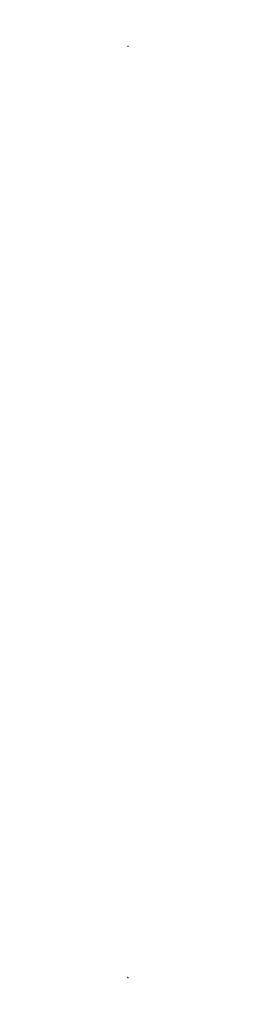
SolidWorks assembly PCB, configuration 默认. Lengths in mm.
Overall size (86.32 130845.02 99.24).
17 component instances, 7 part files, 34 mates.
Components (placement in the parent):
- MTi-600-series_dev_board_RTK-1: MTi-600-series_dev_board_RTK [默认] at origin size (85.78 22.45 98.7)
- support_v0731-1: support_v0731 [默认] at (-81.6803 0.2238 -42.0386) x (1 0 0) z (0 1 0) size (80 90 3)
- 3D_EverySyncBoard-1: 3D_EverySyncBoard [默认] at (-110.8303 11.2238 -45.0001) x (1 0 0) z (0 1 0) size (69.97 49.97 11.61)
- 3D_sync_ext_board-1: 3D_sync_ext_board [默认] at (-110.8413 130801.7057 -20.0185) x (0.000242 0 -1) z (0 -1 0) size (49.99 69.97 12.3)
- 3D_sync_ext_board-2: 3D_sync_ext_board [默认] at (-110.8301 -4.7762 -19.9999) x (0 0 -1) z (0 -1 0) size (49.99 69.97 12.3)
- 柱3×8-1: 柱3×8 [默认] at (-107.3302 3.2238 -23.5) x (0.724489 0 -0.689286) z (0.689286 0 0.724489) size (5 8 5)
- 柱3×8-2: 柱3×8 [默认] at (-107.3302 3.2238 -66.5) size (5 8 5)
- 柱3×8-3: 柱3×8 [默认] at (-44.3302 3.2238 -23.5) size (5 8 5)
- 柱3×8-4: 柱3×8 [默认] at (-44.3302 3.2238 -66.5) size (5 8 5)
- 柱3×5-1: 柱3×5 [默认] at (-107.3302 -4.7762 -66.4975) size (5 5 5)
- 柱3×5-2: 柱3×5 [默认] at (-107.3302 -4.7762 -23.5) x (0.99913 0 0.041703) z (-0.041703 0 0.99913) size (5 5 5)
- 柱3×5-3: 柱3×5 [默认] at (-44.3302 -4.7762 -66.5) x (0.971109 0 0.238638) z (-0.238638 0 0.971109) size (5 5 5)
- 柱3×5-4: 柱3×5 [默认] at (-44.3302 -4.7762 -23.5) x (0.996166 0 -0.08748) z (0.08748 0 0.996166) size (5 5 5)
- 柱3×35-1: 柱3×35 [默认] at (-38.8302 -34.7762 -3) x (-0.944478 0 -0.328574) z (0.328574 0 -0.944478) size (5 35 5)
- 柱3×35-2: 柱3×35 [默认] at (-112.8302 -34.7762 -3) x (0.707262 0 0.706951) z (-0.706951 0 0.707262) size (5 35 5)
- 柱3×35-3: 柱3×35 [默认] at (-38.8302 -34.7762 -87) size (5 35 5)
- 柱3×35-4: 柱3×35 [默认] at (-112.8302 -34.7762 -87) x (0.478155 0 -0.878275) z (0.878275 0 0.478155) size (5 35 5)
Mates (geometry in assembly coordinates):
- 同心3: concentric anti-aligned: cylinder of support_v0731-1 through (-44.3302 3.2248 -66.5) axis (0 -1 0) radius 1.65; cylinder of 3D_sync_ext_board-1 through (-44.3302 130801.7057 -66.5) axis (0 1 0) radius 1.6
- 同心4: concentric anti-aligned: cylinder of support_v0731-1 through (-44.3302 3.2248 -66.5) axis (0 -1 0) radius 1.65; cylinder of 3D_sync_ext_board-2 through (-44.3302 -4.7762 -66.5) axis (0 1 0) radius 1.6
- 同心5: concentric anti-aligned: cylinder of support_v0731-1 through (-107.3302 3.2248 -23.5) axis (0 -1 0) radius 1.65; cylinder of 3D_sync_ext_board-2 through (-107.3302 -4.7762 -23.5) axis (0 1 0) radius 1.6
- 同心9: concentric aligned: cylinder of support_v0731-1 through (-107.3302 3.2248 -23.5) axis (0 -1 0) radius 1.65; cylinder of 3D_EverySyncBoard-1 through (-107.3302 11.2238 -23.5) axis (0 -1 0) radius 1.6
- 同心10: concentric aligned: cylinder of support_v0731-1 through (-44.3302 3.2248 -66.5) axis (0 -1 0) radius 1.65; cylinder of 3D_EverySyncBoard-1 through (-44.3302 11.2238 -66.5) axis (0 -1 0) radius 1.6
- 同心11: concentric aligned: cylinder of support_v0731-1 through (-107.3302 3.2248 -23.5) axis (0 -1 0) radius 1.65; cylinder of 柱3×8-1 through (-107.3302 11.2238 -23.5) axis (0 -1 0) radius 1.5
- 重合1: coincident anti-aligned: plane of support_v0731-1 through (-81.6803 3.2238 -42.0386) normal (0 1 0); plane of 柱3×8-1 through (-107.3302 3.2238 -23.5) normal (0 -1 0)
- 重合2: coincident anti-aligned: plane of 3D_EverySyncBoard-1 through (-75.8303 11.2238 -45.0001) normal (0 -1 0); plane of 柱3×8-1 through (-107.3302 11.2238 -23.5) normal (0 1 0)
- 同心12: concentric aligned: cylinder of support_v0731-1 through (-107.3302 3.2248 -66.5) axis (0 -1 0) radius 1.65; cylinder of 柱3×8-2 through (-107.3302 11.2238 -66.5) axis (0 -1 0) radius 1.5
- 重合3: coincident anti-aligned: plane of support_v0731-1 through (-81.6803 3.2238 -42.0386) normal (0 1 0); plane of 柱3×8-2 through (-107.3302 3.2238 -66.5) normal (0 -1 0)
- 同心13: concentric aligned: cylinder of support_v0731-1 through (-44.3302 3.2248 -66.5) axis (0 -1 0) radius 1.65; cylinder of 柱3×8-4 through (-44.3302 11.2238 -66.5) axis (0 -1 0) radius 1.5
- 重合4: coincident anti-aligned: plane of support_v0731-1 through (-81.6803 3.2238 -42.0386) normal (0 1 0); plane of 柱3×8-4 through (-44.3302 3.2238 -66.5) normal (0 -1 0)
- 同心14: concentric aligned: cylinder of support_v0731-1 through (-44.3302 3.2248 -23.5) axis (0 -1 0) radius 1.65; cylinder of 柱3×8-3 through (-44.3302 11.2238 -23.5) axis (0 -1 0) radius 1.5
- 重合5: coincident anti-aligned: plane of support_v0731-1 through (-81.6803 3.2238 -42.0386) normal (0 1 0); plane of 柱3×8-3 through (-44.3302 3.2238 -23.5) normal (0 -1 0)
- 同心15: concentric anti-aligned: cylinder of 3D_sync_ext_board-2 through (-107.3302 -4.7762 -66.4975) axis (0 1 0) radius 1.6; cylinder of 柱3×5-1 through (-107.3302 0.2238 -66.4975) axis (0 -1 0) radius 1.5
- 重合6: coincident anti-aligned: plane of support_v0731-1 through (-81.6803 0.2238 -42.0386) normal (0 -1 0); plane of 柱3×5-1 through (-107.3302 0.2238 -66.4975) normal (0 1 0)
- 同心16: concentric aligned: cylinder of support_v0731-1 through (-107.3302 3.2248 -23.5) axis (0 -1 0) radius 1.65; cylinder of 柱3×5-2 through (-107.3302 0.2238 -23.5) axis (0 -1 0) radius 1.5
- 重合7: coincident anti-aligned: plane of support_v0731-1 through (-81.6803 0.2238 -42.0386) normal (0 -1 0); plane of 柱3×5-2 through (-107.3302 0.2238 -23.5) normal (0 1 0)
- 同心17: concentric aligned: cylinder of support_v0731-1 through (-44.3302 3.2248 -23.5) axis (0 -1 0) radius 1.65; cylinder of 柱3×5-4 through (-44.3302 0.2238 -23.5) axis (0 -1 0) radius 1.5
- 重合8: coincident anti-aligned: plane of support_v0731-1 through (-81.6803 0.2238 -42.0386) normal (0 -1 0); plane of 柱3×5-4 through (-44.3302 0.2238 -23.5) normal (0 1 0)
- 同心18: concentric aligned: cylinder of support_v0731-1 through (-44.3302 3.2248 -66.5) axis (0 -1 0) radius 1.65; cylinder of 柱3×5-3 through (-44.3302 0.2238 -66.5) axis (0 -1 0) radius 1.5
- 重合9: coincident anti-aligned: plane of support_v0731-1 through (-81.6803 0.2238 -42.0386) normal (0 -1 0); plane of 柱3×5-3 through (-44.3302 0.2238 -66.5) normal (0 1 0)
- 重合10: coincident anti-aligned: plane of 3D_sync_ext_board-2 through (-75.8301 -4.7762 -44.9999) normal (0 1 0); plane of 柱3×5-3 through (-44.3302 -4.7762 -66.5) normal (0 -1 0)
- 重合16: coincident anti-aligned: plane of MTi-600-series_dev_board_RTK-1 through (-35.8302 -34.7762 -0.9) normal (0 1 0); plane of 柱3×35-2 through (-112.8302 -34.7762 -3) normal (0 -1 0)
- 同心23: concentric aligned: cylinder of MTi-600-series_dev_board_RTK-1 through (-112.8302 -36.4182 -3) axis (0 -1 0) radius 1.55; cylinder of 柱3×35-2 through (-112.8302 0.2238 -3) axis (0 -1 0) radius 1.5
- 重合20: coincident anti-aligned: plane of MTi-600-series_dev_board_RTK-1 through (-35.8302 -34.7762 -0.9) normal (0 1 0); plane of 柱3×35-1 through (-38.8302 -34.7762 -3) normal (0 -1 0)
- 同心26: concentric aligned: cylinder of MTi-600-series_dev_board_RTK-1 through (-38.8302 -36.4182 -3) axis (0 -1 0) radius 1.55; cylinder of 柱3×35-1 through (-38.8302 0.2238 -3) axis (0 -1 0) radius 2.5
- 重合22: coincident anti-aligned: plane of MTi-600-series_dev_board_RTK-1 through (-35.8302 -34.7762 -0.9) normal (0 1 0); plane of 柱3×35-4 through (-112.8302 -34.7762 -87) normal (0 -1 0)
- 同心27: concentric aligned: cylinder of MTi-600-series_dev_board_RTK-1 through (-112.8302 -36.4182 -87) axis (0 -1 0) radius 1.55; cylinder of 柱3×35-4 through (-112.8302 0.2238 -87) axis (0 -1 0) radius 1.5
- 同心28: concentric aligned: cylinder of MTi-600-series_dev_board_RTK-1 through (-38.8302 -36.4182 -87) axis (0 -1 0) radius 1.55; cylinder of 柱3×35-3 through (-38.8302 0.2238 -87) axis (0 -1 0) radius 1.5
- 重合23: coincident anti-aligned: plane of MTi-600-series_dev_board_RTK-1 through (-35.8302 -34.7762 -0.9) normal (0 1 0); plane of 柱3×35-3 through (-38.8302 -34.7762 -87) normal (0 -1 0)
- 同心29: concentric aligned: cylinder of support_v0731-1 through (-38.8302 3.2238 -87) axis (0 -1 0) radius 1.65; cylinder of 柱3×35-3 through (-38.8302 0.2238 -87) axis (0 -1 0) radius 1.5
- 同心30: concentric aligned: cylinder of support_v0731-1 through (-112.8302 3.2238 -3) axis (0 -1 0) radius 1.65; cylinder of 柱3×35-2 through (-112.8302 0.2238 -3) axis (0 -1 0) radius 1.5
- 重合25: coincident anti-aligned: plane of support_v0731-1 through (-81.6803 0.2238 -42.0386) normal (0 -1 0); plane of 柱3×35-2 through (-112.8302 0.2238 -3) normal (0 1 0)
